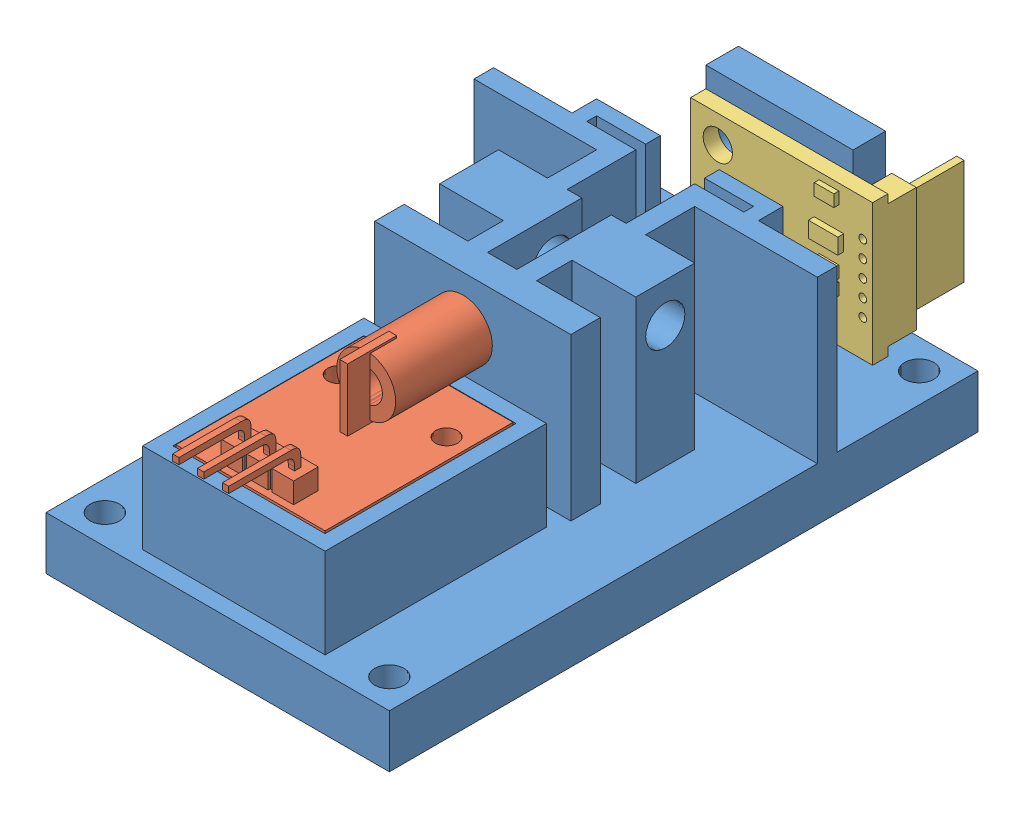
SolidWorks assembly MeasuringModule-V3, configuration Default. Lengths in mm.
Overall size (35 21.85 67.06).
4 component instances, 4 part files, 8 mates.
Components (placement in the parent):
- MeasuringRigBody-V3-1: MeasuringRigBody-V3 [Default] at origin size (35 21.85 60)
- Laser-1: Laser [Default] at (0 14.65 17.075) size (15.2 9.36 26.73)
- Laser-Sensor-V2-1: Laser-Sensor-V2 [Default] at (2.36 12.57 -26.6736) x (0 1 0) z (1 0 0) size (14.36 10.9 18.55)
- MeasuringRigCover-V3-1: MeasuringRigCover-V3 [Default] at origin size (40 24.85 65) (hidden)
Mates (geometry in assembly coordinates):
- Parallel1: parallel anti-aligned: plane of MeasuringRigBody-V3-1 through (0 5.39 0) normal (0 1 0); plane of Laser-1 through (0 13.05 17.075) normal (0 -1 0)
- Concentric1: concentric anti-aligned: cylinder of MeasuringRigBody-V3-1 through (0 17.85 8.2426) axis (0 0 -1) radius 1.5; cylinder of Laser-1 through (0 17.85 5.005) axis (0 0 1) radius 3
- Parallel3: parallel anti-aligned: plane of MeasuringRigBody-V3-1 through (0 5.39 0) normal (0 1 0); plane of Laser-Sensor-1 through (11.635 5.39 -25.1236) normal (0 -1 0)
- Parallel4: parallel aligned: plane of MeasuringRigBody-V3-1 through (-17.5 5.39 -30) normal (0 0 -1); plane of Laser-Sensor-1 through (2.36 12.57 -26.6736) normal (0 0 -1)
- Coincident14: coincident anti-aligned: plane of MeasuringRigBody-V3-1 through (0 5.39 0) normal (0 1 0); plane of Laser-Sensor-1 through (11.635 5.39 -25.1236) normal (0 -1 0)
- Distance2: distance = 16.5 mm anti-aligned: plane of Laser-Sensor-1 through (2.36 12.57 -25.1236) normal (0 0 1); plane of MeasuringRigBody-V3-1 through (-10 42.7306 -8.6236) normal (0 0 -1)
- Coincident21: coincident: line of Laser-1 through (0 17.85 15.7522) axis (0 0 -1); plane of Laser-Sensor-1 through (0 12.57 -26.6736) normal (-1 0 0)
- Concentric2: concentric aligned: cylinder of MeasuringRigBody-V3-1 through (5.5 0 12.17) axis (0 1 0) radius 0.75; cylinder of Laser-1 through (5.5 13.05 12.17) axis (0 1 0) radius 1.125
